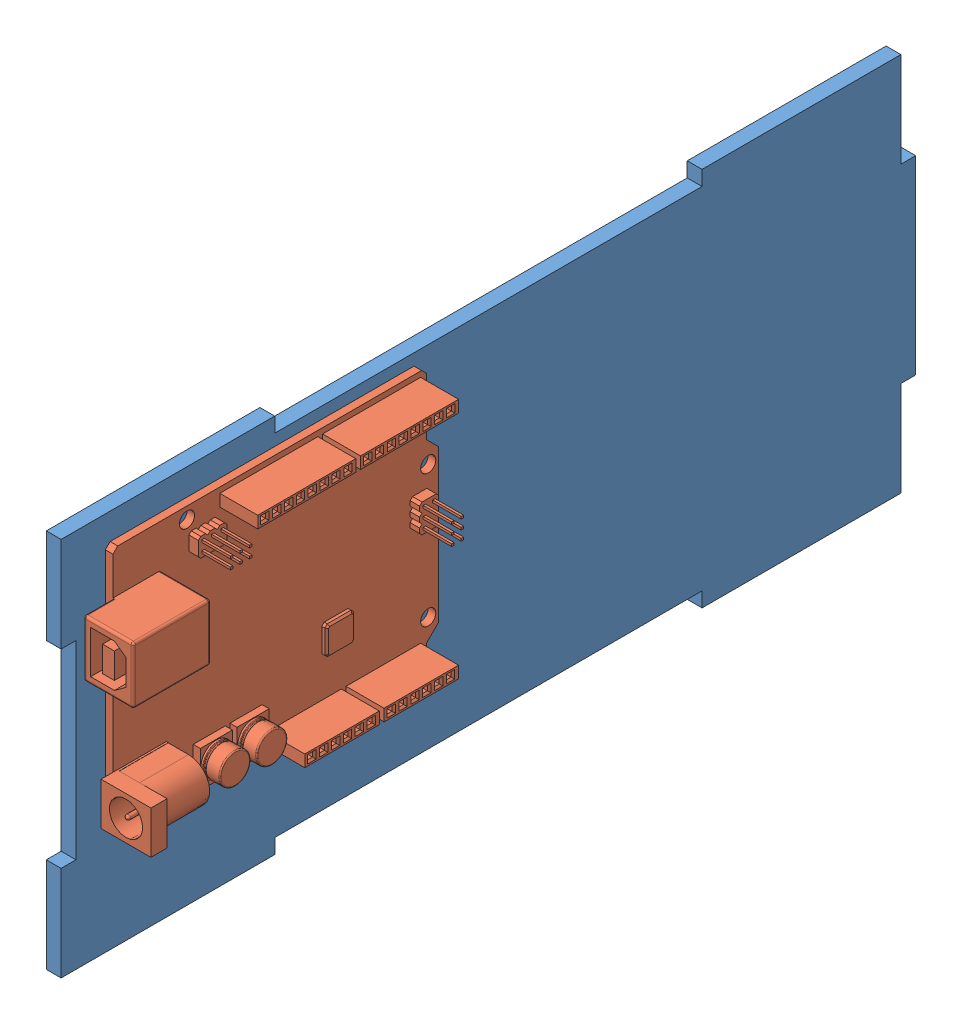
SolidWorks assembly arduino thingy, configuration Default. Lengths in mm.
Overall size (15.22 80 180).
2 component instances, 2 part files, 2 mates.
Components (placement in the parent):
- RightLeft,Useless bobobobobx-2: RightLeft,Useless bobobobobx [Default] at (-157.3405 33.7418 84.1716) size (3.12 80 180)
- ArduinoUno-1: ArduinoUno [Default] at (-154.2205 41.5409 131.8516) x (0 0 -1) z (0 -1 0) size (74.8 12.1 53.3)
Mates (geometry in assembly coordinates):
- Coincident4: coincident anti-aligned: plane of RightLeft,Useless bobobobobx-2 through (-154.2205 33.7418 84.1716) normal (1 0 0); plane of ArduinoUno-1 through (-154.2205 68.1909 98.8516) normal (-1 0 0)
- Coincident6: coincident: line of RightLeft,Useless bobobobobx-2 through (-154.2205 13.7418 171.0516) axis (0 1 0); plane of ArduinoUno-1 through (-142.1205 59.1909 171.0516) normal (0 0 1)
